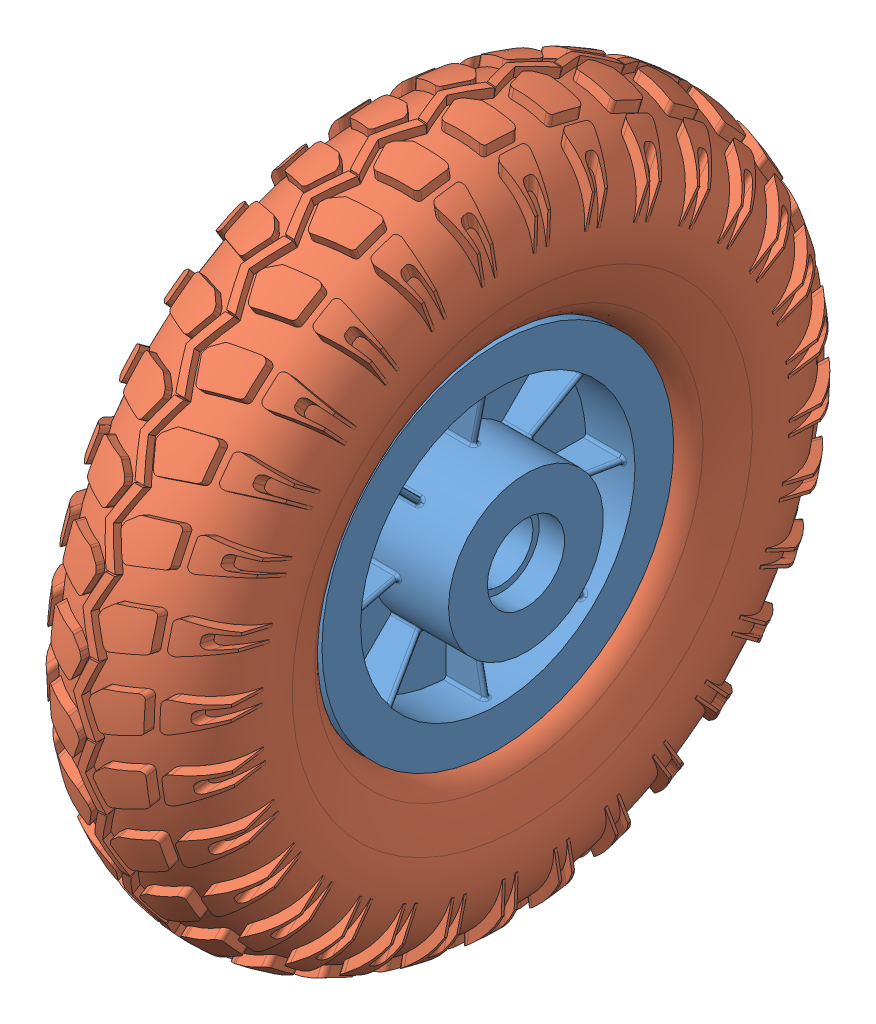
SolidWorks assembly Wheel Cross Section, configuration Default. Lengths in mm.
Overall size (353.85 245.18 252.03).
5 component instances, 5 part files, 8 mates.
Components (placement in the parent):
- Rim-1: Rim [Default] at (29.9151 47.7032 83.7151) size (50 100 100)
- Tire-1: Tire [Default] at (29.9151 47.7032 83.7151) x (1 0 0) z (0 -0.972182 0.234225) size (353.85 210.71 201.43)
- Shaft connector Artilon-1: Shaft connector Artilon [Default] at (4.8849 47.7032 83.7151) x (-1 0 0) z (0 0.92388 0.382683) size (35 28 28)
- Motor Shaft-1: Motor Shaft [Default] at (-10.1151 47.7032 83.7151) x (1 0 0) z (0 0.92388 0.382683) size (43 8 8)
- Screw 5mm - short-1: Screw 5mm - short [Default] at (15.8849 57.3747 60.366) x (-0.904574 -0.393865 -0.163144) z (0.426317 -0.835717 -0.346165) size (10 25.49 10)
Mates (geometry in assembly coordinates):
- Concentric1: concentric aligned: cylinder of Rim-1 through (-147.0108 47.7032 83.7151) axis (-1 0 0) radius 11; cylinder of Shaft connector Artilon-1 through (22.8849 47.7032 83.7151) axis (-1 0 0) radius 9.2
- Concentric2: concentric aligned: cylinder of Rim-1 through (15.8849 72.7037 23.3585) axis (0 -0.382683 0.92388) radius 2.5; cylinder of Shaft connector Artilon-1 through (15.8849 51.53 74.4763) axis (0 -0.382683 0.92388) radius 2.5
- Concentric3: concentric aligned: cylinder of Shaft connector Artilon-1 through (22.8849 47.7032 83.7151) axis (-1 0 0) radius 4; cylinder of Motor Shaft-1 through (22.8849 47.7032 83.7151) axis (-1 0 0) radius 4
- Coincident3: coincident anti-aligned: plane of Shaft connector Artilon-1 through (22.8849 44.0077 82.1843) normal (-1 0 0); plane of Motor Shaft-1 through (22.8849 47.7032 83.7151) normal (1 0 0)
- Concentric4: concentric aligned: cylinder of Rim-1 through (-147.0108 47.7032 83.7151) axis (-1 0 0) radius 44; cylinder of Tire-1 through (-147.0108 47.7032 83.7151) axis (-1 0 0) radius 44
- Coincident4: coincident anti-aligned: plane of Rim-1 through (15.9151 47.7032 83.7151) normal (1 0 0); plane of Tire-1 through (15.9151 47.7032 83.7151) normal (-1 0 0)
- Concentric6: concentric anti-aligned: cylinder of Rim-1 through (15.8849 72.7037 23.3585) axis (0 -0.382683 0.92388) radius 2.5; cylinder of Screw 5mm - short-1 through (15.8849 48.8513 80.9434) axis (0 0.382683 -0.92388) radius 2.5
- Coincident7: coincident anti-aligned: plane of Motor Shaft-1 through (22.8849 48.8513 80.9434) normal (0 0.382683 -0.92388); plane of Screw 5mm - short-1 through (15.8849 48.8513 80.9434) normal (0 -0.382683 0.92388)
